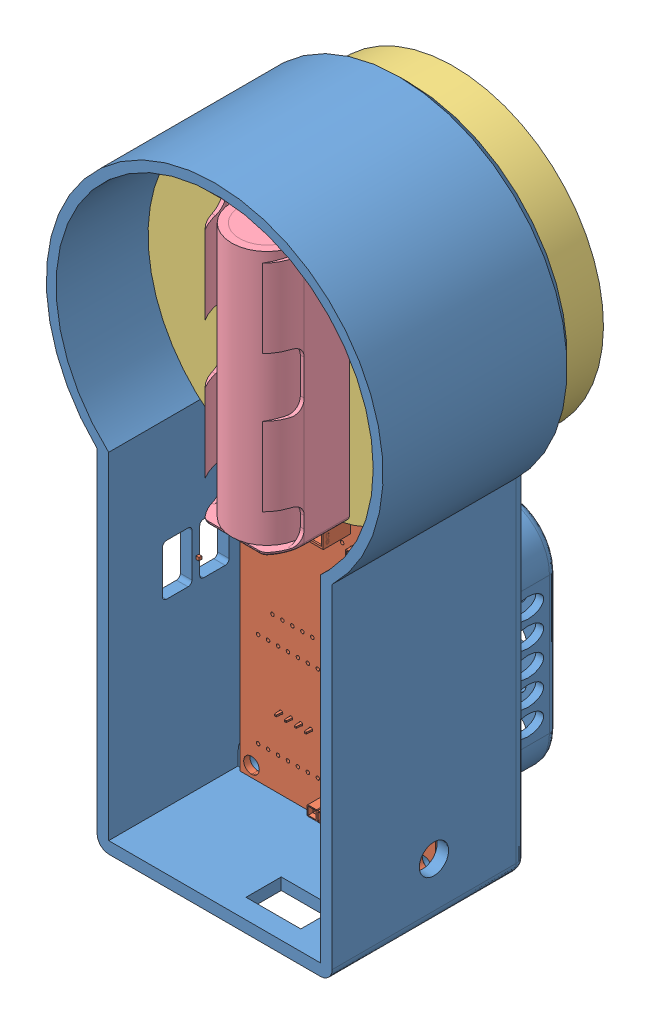
SolidWorks assembly final_product, configuration Default. Lengths in mm.
Overall size (97.61 162 63).
7 component instances, 7 part files, 8 mates.
Components (placement in the parent):
- final_product-1: final_product [Default] at origin size (97.61 162 63)
- final_product_top_cover-1: final_product_top_cover [Default] at (0 0 35) size (86 162 6.17) (hidden)
- Ceilling_mount-1: Ceilling_mount [Default] at (0 0 37) size (36 98.5 6) (hidden)
- circuit-1: circuit [Default] at (-24.9974 -114.5 2) x (0 1 0) z (0 0 1) size (72.72 51.79 19.56)
- Part13^final_product-1: Part13^final_product [Default] at (0 0 -12) (virtual)
- dummy_tuya-1: dummy_tuya [Default] at (1.5576 38.2476 -14.4575) x (0.040691 0.999172 0) z (0.999172 -0.040691 0) size (80 38 80)
- 18650 Battery Holder v5-1: 18650 Battery Holder v5 [Default] at (0.8735 -0.1603 12) size (21 75 19.5)
Mates (geometry in assembly coordinates):
- Concentric1: concentric aligned: cylinder of final_product-1 through (-22.0002 -112.5 2) axis (0 0 -1) radius 2; cylinder of circuit-1 through (-22.0002 -112.5 2) axis (0 0 -1) radius 2
- Coincident1: coincident anti-aligned: plane of final_product-1 through (0 0 2) normal (0 0 1); plane of circuit-1 through (0.0026 -79.0034 2) normal (0 0 -1)
- Parallel1: parallel anti-aligned: plane of final_product-1 through (-27.0602 -33.4177 -12) normal (1 0 0); plane of circuit-1 through (-24.9847 -115.2493 2) normal (-1 0 0)
- Parallel2: parallel aligned: plane of final_product-1 through (0 0 35) normal (0 0 1); plane of dummy_tuya-1 through (1.53 37.5689 12) normal (0 0 1)
- Concentric2: concentric aligned: circle of final_product-1; circle of dummy_tuya-1
- Coincident2: coincident aligned: circle of final_product-1; circle of dummy_tuya-1
- Coincident4: coincident anti-aligned: plane of dummy_tuya-1 through (1.53 37.5689 12) normal (0 0 1); plane of 1s_Liion-1 through (23.8185 -1.6322 12) normal (0 0 -1)
- Coincident5: coincident anti-aligned: plane of dummy_tuya-1 through (1.53 37.5689 12) normal (0 0 1); plane of 18650 Battery Holder v5-1 through (0.8735 -0.1603 12) normal (0 0 -1)
